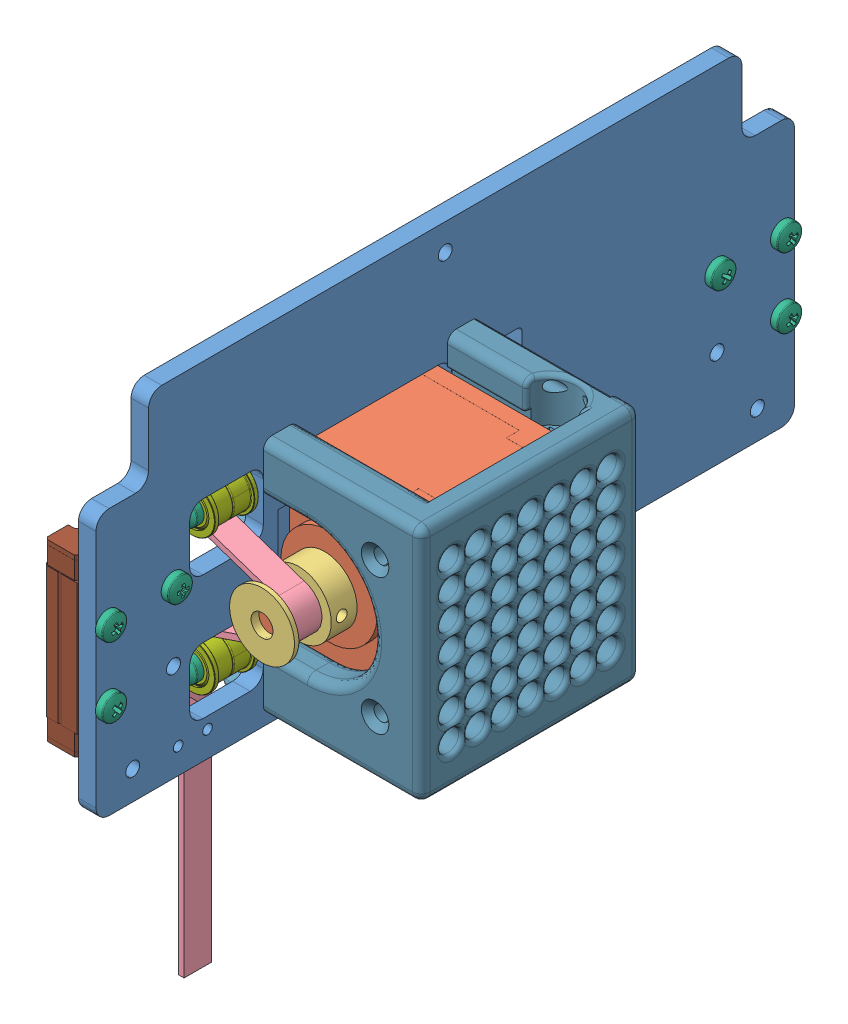
SolidWorks assembly Y table support assembly, configuration Default. Lengths in mm.
Overall size (50.59 135.83 161.6).
55 component instances, 16 part files, 38 mates.
Components (placement in the parent):
- Bed Support2-1: Bed Support2 [Default] at (158.1541 -22.9696 116.2539) x (0 0 -1) z (-1 0 0) size (159.38 135.83 4)
- Y motor assembly-1: Y motor assembly [Default] at (168.1541 -79.5498 18.7526) size (45.38 121.74 63.16)
  - Steper Motor (42HD0401-24, 34mm)-1: Steper Motor (42HD0401-24, 34mm) [Default] at origin size (42.1 42.1 48.5)
  - Timing Gear 15 touth MXL-1: Timing Gear 15 touth MXL [Valor predeterminado] at (0 0 52.5) x (0 0 -1) z (-0.874709 0.484649 0) size (14.3 14.8 14.8)
  - Y Belt (MXL 6mm)-1: Y Belt (MXL 6mm) [Default] at (-23 121.3613 41.9) x (1 0 0) z (0 0 -1) size (26.58 121.74 6.2)
  - Y motor Bracket-1: Y motor Bracket [Default] at (-14 94.6889 -26.0539) x (0 0 1) z (-1 0 0) size (50 56.1 5)
  - countersunk flat head cross recess screw_iso-1: countersunk flat head cross recess screw_iso [ISO 7046-1 - M3 x 10 - Z --- 10N] at (-18.5 -24.05 -6) x (1 0 0) z (0 0.002468 0.999997) (suppressed, hidden)
  - countersunk flat head cross recess screw_iso-2: countersunk flat head cross recess screw_iso [ISO 7046-1 - M3 x 10 - Z --- 10N] at (-18.5 24.05 -6) x (1 0 0) z (0 0.007553 0.999971) (suppressed, hidden)
  - countersunk flat head cross recess screw_iso-3: countersunk flat head cross recess screw_iso [ISO 7046-1 - M3 x 10 - Z --- 10N] at (-18.5 24.05 36) x (1 0 0) z (0 0.006807 0.999977) (suppressed, hidden)
  - countersunk flat head cross recess screw_iso-4: countersunk flat head cross recess screw_iso [ISO 7046-1 - M3 x 10 - Z --- 10N] at (-18.5 -24.05 36) x (1 0 0) z (0 -0.951926 0.306327) (suppressed, hidden)
  - pan head cross recess screw_iso-1: pan head cross recess screw_iso [ISO 7045 - M3 x 25 - Z --- 25N] at (-15.5 15.5 53.2076) x (0 0 -1) z (0.557785 0.829985 0) size (27.35 5.6 5.6)
  - pan head cross recess screw_iso-2: pan head cross recess screw_iso [ISO 7045 - M3 x 25 - Z --- 25N] at (-15.5 -15.5 53.2076) x (0 0 -1) z (-0.131636 -0.991298 0) size (27.35 5.6 5.6)
  - pan head cross recess screw_iso-3: pan head cross recess screw_iso [ISO 7045 - M2 x 10 - Z --- 10N] at (-15.5 15.5 -11.04) x (0 0 1) z (0.720748 0.693197 0) (suppressed, hidden)
  - pan head cross recess screw_iso-4: pan head cross recess screw_iso [ISO 7045 - M2 x 10 - Z --- 10N] at (-15.5 -15.5 -11.04) x (0 0 1) z (0.999705 -0.0243 0) (suppressed, hidden)
  - Bearing assembly1-1: Bearing assembly1 [Default] at (-16.1213 -13.0357 48.1731) x (0 0 -1) z (-0.272283 0.962217 0) size (10.81 13.72 13.72)
    - Idler Bearing (F603HZZ) Assembly-1: Idler Bearing (F603HZZ) Assembly [Default] at (4.8712 0.0732 -2.5403) size (5 10.49 10.49)
      - Idler Bearing (F603HZZ) part 1-1: Idler Bearing (F603HZZ) part 1 [Default] at origin size (5 10.49 10.49)
      - Idler Bearing (F603HZZ) part 2-1: Idler Bearing (F603HZZ) part 2 [Default] at origin size (3.13 7.92 8.2)
      - Idler Bearing (F603HZZ) part 3-1: Idler Bearing (F603HZZ) part 3 [Default] at origin size (5 4.24 4.24)
    - Idler Bearing (F603HZZ) Assembly-2: Idler Bearing (F603HZZ) Assembly [Default] at (-0.1326 0.0732 -2.5403) x (-1 0 0) z (0 -0.922978 -0.384852) size (5 10.49 10.49)
      - Idler Bearing (F603HZZ) part 1-1: Idler Bearing (F603HZZ) part 1 [Default] at origin size (5 10.49 10.49)
      - Idler Bearing (F603HZZ) part 2-1: Idler Bearing (F603HZZ) part 2 [Default] at origin size (3.13 7.92 8.2)
      - Idler Bearing (F603HZZ) part 3-1: Idler Bearing (F603HZZ) part 3 [Default] at origin size (5 4.24 4.24)
    - plain washer 10673 type snl_iso-1: plain washer 10673 type snl_iso [ISO 10673-3.2-S] at (7.3731 0.0732 -2.5403) x (1 0 0) z (0 0.016518 0.999864) size (0.8 7 7)
  - Bearing assembly1-2: Bearing assembly1 [Default] at (-16.3234 17.9043 48.1731) x (0 0 -1) z (-0.351111 0.936334 0) size (10.81 13.72 13.72)
    - Idler Bearing (F603HZZ) Assembly-1: Idler Bearing (F603HZZ) Assembly [Default] at (4.8712 0.0732 -2.5403) size (5 10.49 10.49)
      - Idler Bearing (F603HZZ) part 1-1: Idler Bearing (F603HZZ) part 1 [Default] at origin size (5 10.49 10.49)
      - Idler Bearing (F603HZZ) part 2-1: Idler Bearing (F603HZZ) part 2 [Default] at origin size (3.13 7.92 8.2)
      - Idler Bearing (F603HZZ) part 3-1: Idler Bearing (F603HZZ) part 3 [Default] at origin size (5 4.24 4.24)
    - Idler Bearing (F603HZZ) Assembly-2: Idler Bearing (F603HZZ) Assembly [Default] at (-0.1326 0.0732 -2.5403) x (-1 0 0) z (0 -0.922978 -0.384852) size (5 10.49 10.49)
      - Idler Bearing (F603HZZ) part 1-1: Idler Bearing (F603HZZ) part 1 [Default] at origin size (5 10.49 10.49)
      - Idler Bearing (F603HZZ) part 2-1: Idler Bearing (F603HZZ) part 2 [Default] at origin size (3.13 7.92 8.2)
      - Idler Bearing (F603HZZ) part 3-1: Idler Bearing (F603HZZ) part 3 [Default] at origin size (5 4.24 4.24)
    - plain washer 10673 type snl_iso-1: plain washer 10673 type snl_iso [ISO 10673-3.2-S] at (7.3731 0.0732 -2.5403) x (1 0 0) z (0 0.016518 0.999864) size (0.8 7 7)
  - hex thin nut chamfered gradeab_iso-1: hex thin nut chamfered gradeab_iso [Hexagon Thin Nut ISO - 4035 - M3 - N] at (-8.2 24.05 -6) x (0 0 -1) z (1 0 0) (suppressed, hidden)
  - hex thin nut chamfered gradeab_iso-2: hex thin nut chamfered gradeab_iso [Hexagon Thin Nut ISO - 4035 - M3 - N] at (-8.2 24.05 36) x (0 -0.38321 -0.923661) z (1 0 0) (suppressed, hidden)
  - hex thin nut chamfered gradeab_iso-3: hex thin nut chamfered gradeab_iso [Hexagon Thin Nut ISO - 4035 - M3 - N] at (-8.2 -24.05 36) x (0 0.997465 0.071165) z (1 0 0) (suppressed, hidden)
  - hex thin nut chamfered gradeab_iso-4: hex thin nut chamfered gradeab_iso [Hexagon Thin Nut ISO - 4035 - M3 - N] at (-8.2 -24.05 -6) x (0 0.897045 -0.441939) z (1 0 0) (suppressed, hidden)
- Rail Assembly-1: Rail Assembly [Default] at (150.6541 -79.5498 -52.2469) x (0 0 1) z (0 1 0) size (161.6 14.41 39.97)
  - Rail MGN9-1: Rail MGN9 [Default] at origin size (20 8.06 39.97)
  - Rail MGN9-2: Rail MGN9 [Default] at (139 0 0) size (20 8.06 39.97)
  - pan head cross recess screw_iso-1: pan head cross recess screw_iso [ISO 7045 - M3 x 6 - Z --- 6N] at (7.5 9.9 8) x (0 -1 0) z (-0.780168 0 -0.62557) size (8.35 5.6 5.6)
  - pan head cross recess screw_iso-2: pan head cross recess screw_iso [ISO 7045 - M3 x 6 - Z --- 6N] at (-7.5 9.9 -8) x (0 -1 0) z (0.381849 0 0.924225) size (8.35 5.6 5.6)
  - pan head cross recess screw_iso-3: pan head cross recess screw_iso [ISO 7045 - M3 x 6 - Z --- 6N] at (146.5 9.9 8) x (0 -1 0) z (-0.364107 0 -0.931357) size (8.35 5.6 5.6)
  - pan head cross recess screw_iso-4: pan head cross recess screw_iso [ISO 7045 - M3 x 6 - Z --- 6N] at (131.5 9.9 8) x (0 -1 0) z (0.06083 0 -0.998148) size (8.35 5.6 5.6)
  - pan head cross recess screw_iso-5: pan head cross recess screw_iso [ISO 7045 - M3 x 6 - Z --- 6N] at (146.5 9.9 -8) x (0 -1 0) z (0.647519 0 0.762049) size (8.35 5.6 5.6)
  - pan head cross recess screw_iso-6: pan head cross recess screw_iso [ISO 7045 - M3 x 6 - Z --- 6N] at (-7.5 9.9 8) x (0 -1 0) z (0.381849 0 0.924225) size (8.35 5.6 5.6)
- hex thin nut chamfered gradeab_iso-2: hex thin nut chamfered gradeab_iso [Hexagon Thin Nut ISO - 4035 - M3 - N] at (152.3541 -36.8 17.2531) x (0 0 1) z (-1 0 0)
- Endstop assembly-1: Endstop assembly [Default] at (152.8852 -103.4196 69.2852) x (0 0 -1) z (-1 0 0) size (13.8 11.8 11.57)
  - Endstop Assembly (HT-010-1A-250VAC) - small-1: Endstop Assembly (HT-010-1A-250VAC) - small [Default] at (-0.8242 -1.9413 1.4759) size (13.8 11.8 5.71)
    - Endstop Actuator (HT-010-1A-250VAC)-1: Endstop Actuator (HT-010-1A-250VAC) [Default] at (-9.3436 7.5264 -0.1798) size (12.8 2.57 3.6)
    - Enstop Base (HT-010-1A-250VAC)-1: Enstop Base (HT-010-1A-250VAC) [Default] at (-1.4636 2.6194 0.1552) size (12.83 9.86 5.71)
  - pan head cross recess screw_iso-1: pan head cross recess screw_iso [ISO 7045 - M2 x 10 - Z --- 10N] at (-2.2029 0.4551 6.0461) x (0 0 -1) z (-0.957289 -0.289133 0)
  - pan head cross recess screw_iso-3: pan head cross recess screw_iso [ISO 7045 - M2 x 10 - Z --- 10N] at (-8.9029 0.4551 6.0461) x (0 0 -1) z (1 0 0)
- motorYsupport^Y table support assembly-1: motorYsupport^Y table support assembly [Default] at (158.1541 -22.9696 116.2539) x (0 0 1) z (1 0 0) size (50 54.56 36.26) (virtual)
Mates (geometry in assembly coordinates):
- Coincident78718760: coincident: plane of Y motor assembly-1/Steper Motor (42HD0401-24, 34mm)-1 through (147.1041 -58.4998 51.7526) normal (0 1 0); plane of Bed Support2-1 through (154.1541 -58.4998 4.7526) normal (0 -1 0)
- Coincident78718768: coincident: plane of Bed Support2-1 through (154.1541 -22.9696 116.2539) normal (-1 0 0); plane of Y motor assembly-1/Y motor Bracket-1 through (154.1541 -54.4998 55.7526) normal (1 0 0)
- Concentric4005676: concentric: circle of Bed Support2-1; circle of Y motor assembly-1/Y motor Bracket-1
- Concentric4005679: concentric: cylinder of assembly; cylinder of Bed Support2-1 through (154.1541 -103.5998 54.7526) axis (-1 0 0) radius 1.6; cylinder of Y motor assembly-1/countersunk flat head cross recess screw_iso-4 through (143.3041 -103.5998 54.7526) axis (-1 0 0) radius 1.5
- Tangent1: tangent: plane of Bed Support2-1 through (154.1541 -22.9696 116.2539) normal (-1 0 0); cylinder of Y motor assembly-1/pan head cross recess screw_iso-1 through (152.6541 -64.0498 97.3602) axis (0 0 1) radius 1.5
- Tangent2: tangent: plane of assembly; plane of Bed Support2-1 through (154.1541 -22.9696 116.2539) normal (-1 0 0); cylinder of Y motor assembly-1/pan head cross recess screw_iso-3 through (152.6541 -64.0498 -17.6874) axis (0 0 -1) radius 1.5
- Tangent3: tangent: plane of assembly; plane of Bed Support2-1 through (154.1541 -22.9696 116.2539) normal (-1 0 0); cylinder of Y motor assembly-1/pan head cross recess screw_iso-4 through (152.6541 -95.0498 -17.6874) axis (0 0 -1) radius 1.5
- Tangent4: tangent: plane of Bed Support2-1 through (154.1541 -22.9696 116.2539) normal (-1 0 0); cylinder of Y motor assembly-1/Bearing assembly1-1/Idler Bearing (F603HZZ) Assembly-2/Idler Bearing (F603HZZ) part 3-1 through (152.6541 -95.0498 64.3063) axis (0 0 1) radius 1.4986
- Coincident78718773: coincident: plane of Bed Support2-1 through (154.1541 -22.9696 116.2539) normal (-1 0 0); plane of Rail Assembly-1/Rail MGN9-1 through (154.1541 -94.4998 -47.3469) normal (1 0 0)
- Concentric4005686: concentric: cylinder of Bed Support2-1 through (158.1541 -71.5498 -44.7469) axis (1 0 0) radius 1.6; cylinder of Rail Assembly-1/Rail MGN9-1 through (154.1541 -71.5498 -44.7469) axis (-1 0 0) radius 1.25
- Coincident78718774: coincident: plane of Bed Support2-1 through (154.1541 -22.9696 116.2539) normal (-1 0 0); plane of Rail Assembly-1/Rail MGN9-2 through (154.1541 -94.4998 91.6531) normal (1 0 0)
- Concentric4005687: concentric: cylinder of Bed Support2-1 through (158.1541 -71.5498 -44.7469) axis (1 0 0) radius 1.6; cylinder of Rail Assembly-1/pan head cross recess screw_iso-1 through (185.9541 -71.5498 -44.7469) axis (1 0 0) radius 2.8
- Coincident78718775: coincident: plane of Bed Support2-1 through (158.1541 -22.9696 116.2539) normal (1 0 0); plane of Rail Assembly-1/pan head cross recess screw_iso-1 through (158.1541 -70.3796 -45.6853) normal (-1 0 0)
- Concentric4005688: concentric: cylinder of Bed Support2-1 through (158.1541 -87.5498 -59.7469) axis (1 0 0) radius 1.6; cylinder of Rail Assembly-1/pan head cross recess screw_iso-2 through (185.9541 -87.5498 -59.7469) axis (1 0 0) radius 2.8
- Coincident78718776: coincident: plane of Bed Support2-1 through (158.1541 -22.9696 116.2539) normal (1 0 0); plane of Rail Assembly-1/pan head cross recess screw_iso-2 through (158.1541 -88.1226 -58.3606) normal (-1 0 0)
- Concentric4005689: concentric: cylinder of Bed Support2-1 through (158.1541 -71.5498 94.2531) axis (1 0 0) radius 1.6; cylinder of Rail Assembly-1/pan head cross recess screw_iso-3 through (185.9541 -71.5498 94.2531) axis (1 0 0) radius 2.8
- Coincident78718777: coincident: plane of Bed Support2-1 through (158.1541 -22.9696 116.2539) normal (1 0 0); plane of Rail Assembly-1/pan head cross recess screw_iso-3 through (158.1541 -71.0037 92.8561) normal (-1 0 0)
- Concentric4005690: concentric: cylinder of Bed Support2-1 through (158.1541 -71.5498 79.2531) axis (1 0 0) radius 1.6; cylinder of Rail Assembly-1/pan head cross recess screw_iso-4 through (185.9541 -71.5498 79.2531) axis (1 0 0) radius 2.8
- Coincident78718778: coincident: plane of Bed Support2-1 through (158.1541 -22.9696 116.2539) normal (1 0 0); plane of Rail Assembly-1/pan head cross recess screw_iso-4 through (158.1541 -71.6411 77.7559) normal (-1 0 0)
- Concentric4005691: concentric: cylinder of Bed Support2-1 through (158.1541 -87.5498 94.2531) axis (1 0 0) radius 1.6; cylinder of Rail Assembly-1/pan head cross recess screw_iso-5 through (185.9541 -87.5498 94.2531) axis (1 0 0) radius 1.5
- Coincident78718779: coincident: plane of Bed Support2-1 through (158.1541 -22.9696 116.2539) normal (1 0 0); plane of Rail Assembly-1/pan head cross recess screw_iso-5 through (158.1541 -88.5211 95.3962) normal (-1 0 0)
- Concentric4005692: concentric: cylinder of Bed Support2-1 through (158.1541 -71.5498 -59.7469) axis (1 0 0) radius 1.6; cylinder of Rail Assembly-1/pan head cross recess screw_iso-6 through (185.9541 -71.5498 -59.7469) axis (1 0 0) radius 2.8
- Coincident78718780: coincident: plane of Bed Support2-1 through (158.1541 -22.9696 116.2539) normal (1 0 0); plane of Rail Assembly-1/pan head cross recess screw_iso-6 through (158.1541 -72.1226 -58.3606) normal (-1 0 0)
- Concentric4005699: concentric: cylinder of assembly; cylinder of Bed Support2-1 through (154.1541 -55.4998 12.7526) axis (-1 0 0) radius 1.6; cylinder of Y motor assembly-1/hex thin nut chamfered gradeab_iso-1 through (134.9166 -55.4998 12.7526) axis (1 0 0) radius 1.5
- Coincident78718788: coincident: plane of assembly; plane of Bed Support2-1 through (158.1541 -22.9696 116.2539) normal (1 0 0); plane of Y motor assembly-1/hex thin nut chamfered gradeab_iso-1 through (158.1541 -52.3244 12.7526) normal (-1 0 0)
- Concentric4005702: concentric: cylinder of Bed Support2-1 through (154.1541 -55.4998 54.7526) axis (-1 0 0) radius 1.6; cylinder of Y motor assembly-1/hex thin nut chamfered gradeab_iso-2 through (134.9166 -55.4998 54.7526) axis (1 0 0) radius 1.5
- Coincident78718791: coincident: plane of Bed Support2-1 through (158.1541 -22.9696 116.2539) normal (1 0 0); plane of Y motor assembly-1/hex thin nut chamfered gradeab_iso-2 through (158.1541 -52.5668 53.5358) normal (-1 0 0)
- Coincident78718792: coincident: plane of assembly; plane of Bed Support2-1 through (158.1541 -22.9696 116.2539) normal (1 0 0); plane of Y motor assembly-1/hex thin nut chamfered gradeab_iso-3 through (158.1541 -103.8258 57.92) normal (-1 0 0)
- Coincident78718793: coincident: plane of assembly; plane of Bed Support2-1 through (158.1541 -22.9696 116.2539) normal (1 0 0); plane of Y motor assembly-1/hex thin nut chamfered gradeab_iso-4 through (158.1541 -102.1965 15.6011) normal (-1 0 0)
- Concentric4005708: concentric: cylinder of Bed Support2-1 through (158.1541 -36.8 17.2531) axis (1 0 0) radius 1.6; cylinder of hex thin nut chamfered gradeab_iso-2 through (177.3916 -36.8 17.2531) axis (-1 0 0) radius 1.5
- Coincident78718801: coincident: plane of Bed Support2-1 through (154.1541 -22.9696 116.2539) normal (-1 0 0); plane of hex thin nut chamfered gradeab_iso-2 through (154.1541 -33.6246 17.2531) normal (1 0 0)
- Coincident78718785: coincident: plane of Bed Support2-1 through (154.1541 -22.9696 116.2539) normal (-1 0 0); plane of Endstop assembly-1/Endstop Assembly (HT-010-1A-250VAC) - small-1/Enstop Base (HT-010-1A-250VAC)-1 through (154.1541 -102.5977 81.2531) normal (1 0 0)
- Concentric4005715: concentric: cylinder of Bed Support2-1 through (158.1541 -103.8747 71.4881) axis (1 0 0) radius 1.1; cylinder of Endstop assembly-1/pan head cross recess screw_iso-1 through (121.4391 -103.8747 71.4881) axis (-1 0 0) radius 1
- Distance4: distance = 1 mm: plane of Bed Support2-1 through (154.1541 -109.7247 96.9431) normal (0 -1 0); plane of Endstop assembly-1/Endstop Assembly (HT-010-1A-250VAC) - small-1/Enstop Base (HT-010-1A-250VAC)-1 through (154.1541 -108.7247 81.2531) normal (0 -1 0)
- InPlace1: in place: plane of Bed Support2-1 through (158.1541 -22.9696 116.2539) normal (1 0 0); plane of ? through (158.1541 0 0) normal (1 0 0); moOrthogonalPlaneRef_w of Bed Support2-1 through (158.1541 -22.9696 116.2539) normal (1 0 0); plane of ? through (158.1541 0 0) normal (0 1 0); plane of Bed Support2-1 through (158.1541 -22.9696 116.2539) normal (1 0 0); plane of ? through (158.1541 0 0) normal (0 0 -1); plane of Bed Support2-1 through (158.1541 -22.9696 116.2539) normal (1 0 0); unknown of motorYsupport^Y table support assembly-1
- Coincident78718802: coincident: plane of Bed Support2-1; plane of motorYsupport^Y table support assembly-1
- Coincident78718803: coincident: moOrthogonalPlaneRef_w of Bed Support2-1 through (158.1541 -22.9696 116.2539) normal (0 -1 0); plane of motorYsupport^Y table support assembly-1 through (158.1541 -22.9696 116.2539) normal (0 -1 0)
- Coincident78718804: coincident: moOrthogonalPlaneRef_w of Bed Support2-1 through (158.1541 -22.9696 116.2539) normal (0 0 -1); plane of motorYsupport^Y table support assembly-1 through (158.1541 -22.9696 116.2539) normal (0 0 1)
